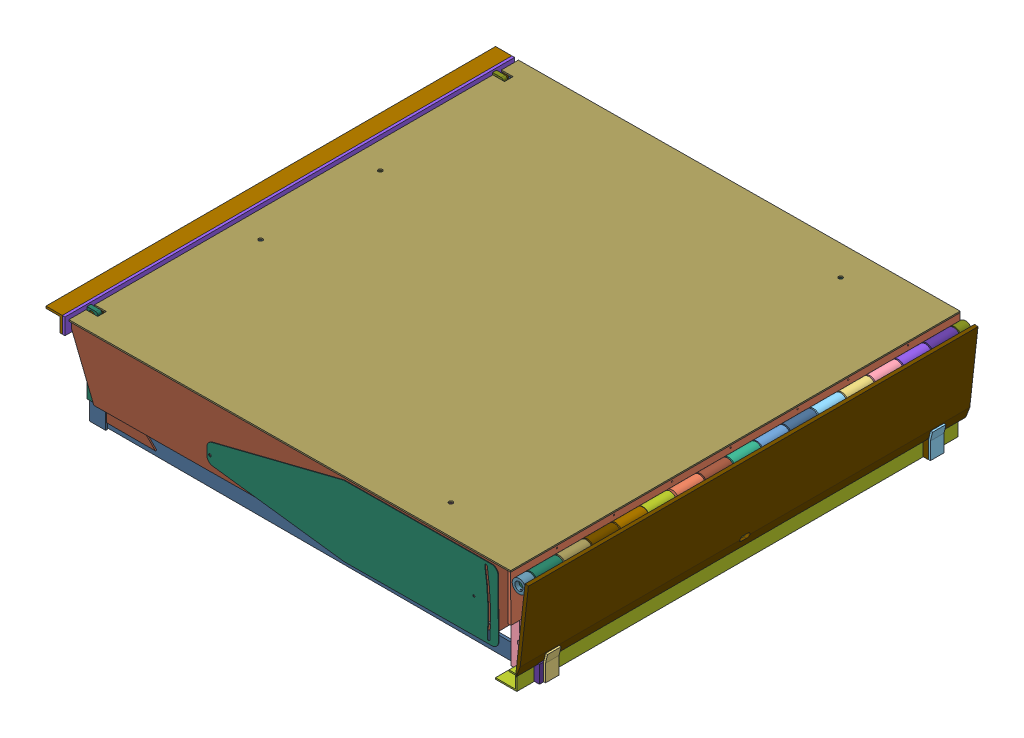
SolidWorks assembly MODELO NH 8X7 60K L16 especial, configuration Predeterminado. Lengths in mm.
Overall size (2261.63 523.31 2108).
138 component instances, 138 part files, 0 mates.
Components (placement in the parent):
- UH-1: UH [Predeterminado] at (-20837.1047 -5434.6461 -22380.9356) x (0 0 1) z (0 -1 0) size (202 682 216)
- MODELO NH 8X7 60K L16 especial2-1: MODELO NH 8X7 60K L16 especial2 [Predeterminado] at origin size (31.58 51.72 76.2)
- MODELO NH 8X7 60K L16 especial3-1: MODELO NH 8X7 60K L16 especial3 [Predeterminado] at origin size (31.58 51.72 76.2)
- MODELO NH 8X7 60K L16 especial4-1: MODELO NH 8X7 60K L16 especial4 [Predeterminado] at origin size (29.63 52.04 76.2)
- MODELO NH 8X7 60K L16 especial5-1: MODELO NH 8X7 60K L16 especial5 [Predeterminado] at origin size (31.58 51.72 76.2)
- MODELO NH 8X7 60K L16 especial6-1: MODELO NH 8X7 60K L16 especial6 [Predeterminado] at origin size (29.63 52.04 76.2)
- MODELO NH 8X7 60K L16 especial7-1: MODELO NH 8X7 60K L16 especial7 [Predeterminado] at origin size (31.58 51.72 76.2)
- MODELO NH 8X7 60K L16 especial8-1: MODELO NH 8X7 60K L16 especial8 [Predeterminado] at origin size (29.63 52.04 76.2)
- MODELO NH 8X7 60K L16 especial9-1: MODELO NH 8X7 60K L16 especial9 [Predeterminado] at origin size (31.58 51.72 76.2)
- MODELO NH 8X7 60K L16 especial10-1: MODELO NH 8X7 60K L16 especial10 [Predeterminado] at origin size (31.58 51.72 76.2)
- MODELO NH 8X7 60K L16 especial11-1: MODELO NH 8X7 60K L16 especial11 [Predeterminado] at origin size (31.58 51.72 76.2)
- MODELO NH 8X7 60K L16 especial12-1: MODELO NH 8X7 60K L16 especial12 [Predeterminado] at origin size (29.63 52.04 76.2)
- MODELO NH 8X7 60K L16 especial13-1: MODELO NH 8X7 60K L16 especial13 [Predeterminado] at origin size (31.58 51.72 76.2)
- MODELO NH 8X7 60K L16 especial14-1: MODELO NH 8X7 60K L16 especial14 [Predeterminado] at origin size (29.63 52.04 76.2)
- MODELO NH 8X7 60K L16 especial15-1: MODELO NH 8X7 60K L16 especial15 [Predeterminado] at origin size (52.14 40.87 51.7)
- MODELO NH 8X7 60K L16 especial16-1: MODELO NH 8X7 60K L16 especial16 [Predeterminado] at origin size (377.14 41.23 25.4)
- MODELO NH 8X7 60K L16 especial17-1: MODELO NH 8X7 60K L16 especial17 [Predeterminado] at origin size (43.03 51.76 50)
- MODELO NH 8X7 60K L16 especial18-1: MODELO NH 8X7 60K L16 especial18 [Predeterminado] at origin size (67.35 52.69 9.5)
- MODELO NH 8X7 60K L16 especial19-1: MODELO NH 8X7 60K L16 especial19 [Predeterminado] at origin size (67.35 52.69 9.5)
- MODELO NH 8X7 60K L16 especial20-1: MODELO NH 8X7 60K L16 especial20 [Predeterminado] at origin size (34.99 66.4 66)
- MODELO NH 8X7 60K L16 especial21-1: MODELO NH 8X7 60K L16 especial21 [Predeterminado] at origin size (270.47 75.91 63.5)
- MODELO NH 8X7 60K L16 especial22-1: MODELO NH 8X7 60K L16 especial22 [Predeterminado] at origin size (30.03 64.53 63.82)
- MODELO NH 8X7 60K L16 especial23-1: MODELO NH 8X7 60K L16 especial23 [Predeterminado] at origin size (92.65 87.43 65.1)
- MODELO NH 8X7 60K L16 especial24-1: MODELO NH 8X7 60K L16 especial24 [Predeterminado] at origin size (575.9 347.01 63.5)
- MODELO NH 8X7 60K L16 especial25-1: MODELO NH 8X7 60K L16 especial25 [Predeterminado] at origin size (612.93 343.69 39.94)
- MODELO NH 8X7 60K L16 especial26-1: MODELO NH 8X7 60K L16 especial26 [Predeterminado] at origin size (55.77 66.38 66)
- MODELO NH 8X7 60K L16 especial27-1: MODELO NH 8X7 60K L16 especial27 [Predeterminado] at origin size (57.33 62.14 50)
- MODELO NH 8X7 60K L16 especial28-1: MODELO NH 8X7 60K L16 especial28 [Predeterminado] at origin size (2082.47 76.2 76.2)
- MODELO NH 8X7 60K L16 especial29-1: MODELO NH 8X7 60K L16 especial29 [Predeterminado] at origin size (2061.6 313.69 2.66)
- MODELO NH 8X7 60K L16 especial30-1: MODELO NH 8X7 60K L16 especial30 [Predeterminado] at origin size (2071.04 22.48 2108)
- MODELO NH 8X7 60K L16 especial31-1: MODELO NH 8X7 60K L16 especial31 [Predeterminado] at origin size (51.86 102.13 19)
- MODELO NH 8X7 60K L16 especial32-1: MODELO NH 8X7 60K L16 especial32 [Predeterminado] at origin size (51.86 102.13 19)
- MODELO NH 8X7 60K L16 especial33-1: MODELO NH 8X7 60K L16 especial33 [Predeterminado] at origin size (19.44 50.15 271.82)
- MODELO NH 8X7 60K L16 especial34-1: MODELO NH 8X7 60K L16 especial34 [Predeterminado] at origin size (1062.97 52.9 50.8)
- MODELO NH 8X7 60K L16 especial35-1: MODELO NH 8X7 60K L16 especial35 [Predeterminado] at origin size (33.39 244.2 2057.2)
- MODELO NH 8X7 60K L16 especial36-1: MODELO NH 8X7 60K L16 especial36 [Predeterminado] at origin size (59.99 397.88 2108)
- MODELO NH 8X7 60K L16 especial37-1: MODELO NH 8X7 60K L16 especial37 [Predeterminado] at origin size (142.05 166.76 2062.76)
- MODELO NH 8X7 60K L16 especial38-1: MODELO NH 8X7 60K L16 especial38 [Predeterminado] at origin size (14.37 215.1 2108)
- MODELO NH 8X7 60K L16 especial39-1: MODELO NH 8X7 60K L16 especial39 [Predeterminado] at origin size (1952.22 175.19 98)
- MODELO NH 8X7 60K L16 especial40-1: MODELO NH 8X7 60K L16 especial40 [Predeterminado] at origin size (1952.22 175.19 98)
- MODELO NH 8X7 60K L16 especial41-1: MODELO NH 8X7 60K L16 especial41 [Predeterminado] at origin size (1952.22 175.19 98)
- MODELO NH 8X7 60K L16 especial42-1: MODELO NH 8X7 60K L16 especial42 [Predeterminado] at origin size (1952.22 175.19 98)
- MODELO NH 8X7 60K L16 especial43-1: MODELO NH 8X7 60K L16 especial43 [Predeterminado] at origin size (1952.22 175.19 98)
- MODELO NH 8X7 60K L16 especial44-1: MODELO NH 8X7 60K L16 especial44 [Predeterminado] at origin size (1952.22 175.19 98)
- MODELO NH 8X7 60K L16 especial45-1: MODELO NH 8X7 60K L16 especial45 [Predeterminado] at origin size (1952.22 175.19 98)
- MODELO NH 8X7 60K L16 especial46-1: MODELO NH 8X7 60K L16 especial46 [Predeterminado] at origin size (1952.22 175.19 98)
- MODELO NH 8X7 60K L16 especial47-1: MODELO NH 8X7 60K L16 especial47 [Predeterminado] at origin size (10.49 63.58 63.5)
- MODELO NH 8X7 60K L16 especial48-1: MODELO NH 8X7 60K L16 especial48 [Predeterminado] at origin size (10.49 63.58 63.5)
- MODELO NH 8X7 60K L16 especial49-1: MODELO NH 8X7 60K L16 especial49 [Predeterminado] at origin size (2061.6 313.69 2.66)
- MODELO NH 8X7 60K L16 especial50-1: MODELO NH 8X7 60K L16 especial50 [Predeterminado] at origin size (63.5 63.5 50)
- MODELO NH 8X7 60K L16 especial51-1: MODELO NH 8X7 60K L16 especial51 [Predeterminado] at origin size (63.5 63.5 127)
- MODELO NH 8X7 60K L16 especial52-1: MODELO NH 8X7 60K L16 especial52 [Predeterminado] at origin size (63.5 63.5 50)
- MODELO NH 8X7 60K L16 especial53-1: MODELO NH 8X7 60K L16 especial53 [Predeterminado] at origin size (63.5 63.5 127)
- MODELO NH 8X7 60K L16 especial54-1: MODELO NH 8X7 60K L16 especial54 [Predeterminado] at origin size (31.75 31.75 2069.2)
- MODELO NH 8X7 60K L16 especial55-1: MODELO NH 8X7 60K L16 especial55 [Predeterminado] at origin size (10.12 76.27 2071.67)
- MODELO NH 8X7 60K L16 especial56-1: MODELO NH 8X7 60K L16 especial56 [Predeterminado] at origin size (51.64 108.34 190.5)
- MODELO NH 8X7 60K L16 especial57-1: MODELO NH 8X7 60K L16 especial57 [Predeterminado] at origin size (51.64 108.34 190.5)
- MODELO NH 8X7 60K L16 especial58-1: MODELO NH 8X7 60K L16 especial58 [Predeterminado] at origin size (76.2 76.2 1859.26)
- MODELO NH 8X7 60K L16 especial59-1: MODELO NH 8X7 60K L16 especial59 [Predeterminado] at origin size (63.25 59.43 19.05)
- MODELO NH 8X7 60K L16 especial60-1: MODELO NH 8X7 60K L16 especial60 [Predeterminado] at origin size (63.25 59.43 19.05)
- MODELO NH 8X7 60K L16 especial61-1: MODELO NH 8X7 60K L16 especial61 [Predeterminado] at origin size (100.01 70 2068.06)
- MODELO NH 8X7 60K L16 especial62-1: MODELO NH 8X7 60K L16 especial62 [Predeterminado] at origin size (12.7 76.2 2108)
- MODELO NH 8X7 60K L16 especial63-1: MODELO NH 8X7 60K L16 especial63 [Predeterminado] at origin size (76.2 76.2 2108)
- MODELO NH 8X7 60K L16 especial64-1: MODELO NH 8X7 60K L16 especial64 [Predeterminado] at origin size (25.4 25.4 847.56)
- MODELO NH 8X7 60K L16 especial65-1: MODELO NH 8X7 60K L16 especial65 [Predeterminado] at origin size (2082.47 76.2 76.2)
- MODELO NH 8X7 60K L16 especial66-1: MODELO NH 8X7 60K L16 especial66 [Predeterminado] at origin size (76.2 417 76.2)
- MODELO NH 8X7 60K L16 especial67-1: MODELO NH 8X7 60K L16 especial67 [Predeterminado] at origin size (63.5 200 28.26)
- MODELO NH 8X7 60K L16 especial68-1: MODELO NH 8X7 60K L16 especial68 [Predeterminado] at origin size (19.55 25.17 28.93)
- MODELO NH 8X7 60K L16 especial69-1: MODELO NH 8X7 60K L16 especial69 [Predeterminado] at origin size (34.92 34.92 2058)
- MODELO NH 8X7 60K L16 especial70-1: MODELO NH 8X7 60K L16 especial70 [Predeterminado] at origin size (63.25 59.43 19.05)
- MODELO NH 8X7 60K L16 especial71-1: MODELO NH 8X7 60K L16 especial71 [Predeterminado] at origin size (63.25 59.43 19.05)
- MODELO NH 8X7 60K L16 especial72-1: MODELO NH 8X7 60K L16 especial72 [Predeterminado] at origin size (63.25 59.43 19.05)
- MODELO NH 8X7 60K L16 especial73-1: MODELO NH 8X7 60K L16 especial73 [Predeterminado] at origin size (63.25 59.43 19.05)
- MODELO NH 8X7 60K L16 especial74-1: MODELO NH 8X7 60K L16 especial74 [Predeterminado] at origin size (63.25 59.43 19.05)
- MODELO NH 8X7 60K L16 especial75-1: MODELO NH 8X7 60K L16 especial75 [Predeterminado] at origin size (21.07 25.05 28.93)
- MODELO NH 8X7 60K L16 especial76-1: MODELO NH 8X7 60K L16 especial76 [Predeterminado] at origin size (25.17 21.07 28.93)
- MODELO NH 8X7 60K L16 especial77-1: MODELO NH 8X7 60K L16 especial77 [Predeterminado] at origin size (25.17 21.07 28.93)
- MODELO NH 8X7 60K L16 especial78-1: MODELO NH 8X7 60K L16 especial78 [Predeterminado] at origin size (25.17 21.07 28.93)
- MODELO NH 8X7 60K L16 especial79-1: MODELO NH 8X7 60K L16 especial79 [Predeterminado] at origin size (25.17 21.07 28.93)
- MODELO NH 8X7 60K L16 especial80-1: MODELO NH 8X7 60K L16 especial80 [Predeterminado] at origin size (86.72 55.18 19.05)
- MODELO NH 8X7 60K L16 especial81-1: MODELO NH 8X7 60K L16 especial81 [Predeterminado] at origin size (53.88 53.88 3.18)
- MODELO NH 8X7 60K L16 especial82-1: MODELO NH 8X7 60K L16 especial82 [Predeterminado] at origin size (83.2 82.19 15.88)
- MODELO NH 8X7 60K L16 especial83-1: MODELO NH 8X7 60K L16 especial83 [Predeterminado] at origin size (68.45 67.53 15.87)
- MODELO NH 8X7 60K L16 especial84-1: MODELO NH 8X7 60K L16 especial84 [Predeterminado] at origin size (53.88 53.88 3.18)
- MODELO NH 8X7 60K L16 especial85-1: MODELO NH 8X7 60K L16 especial85 [Predeterminado] at origin size (83.2 82.19 15.88)
- MODELO NH 8X7 60K L16 especial86-1: MODELO NH 8X7 60K L16 especial86 [Predeterminado] at origin size (68.45 67.53 15.87)
- MODELO NH 8X7 60K L16 especial87-1: MODELO NH 8X7 60K L16 especial87 [Predeterminado] at origin size (1366.94 335.39 2.66)
- MODELO NH 8X7 60K L16 especial88-1: MODELO NH 8X7 60K L16 especial88 [Predeterminado] at origin size (1366.94 335.39 2.66)
- MODELO NH 8X7 60K L16 especial89-1: MODELO NH 8X7 60K L16 especial89 [Predeterminado] at origin size (25.4 81 63.5)
- MODELO NH 8X7 60K L16 especial90-1: MODELO NH 8X7 60K L16 especial90 [Predeterminado] at origin size (25.4 81 63.5)
- MODELO NH 8X7 60K L16 especial91-1: MODELO NH 8X7 60K L16 especial91 [Predeterminado] at origin size (101.65 7.14 246.2)
- MODELO NH 8X7 60K L16 especial92-1: MODELO NH 8X7 60K L16 especial92 [Predeterminado] at origin size (101.65 7.14 246.2)
- MODELO NH 8X7 60K L16 especial93-1: MODELO NH 8X7 60K L16 especial93 [Predeterminado] at origin size (19.05 120 63.5)
- MODELO NH 8X7 60K L16 especial94-1: MODELO NH 8X7 60K L16 especial94 [Predeterminado] at origin size (114.31 236.38 19.08)
- MODELO NH 8X7 60K L16 especial95-1: MODELO NH 8X7 60K L16 especial95 [Predeterminado] at origin size (19.05 120 63.5)
- MODELO NH 8X7 60K L16 especial96-1: MODELO NH 8X7 60K L16 especial96 [Predeterminado] at origin size (114.31 236.38 19.08)
- MODELO NH 8X7 60K L16 especial97-1: MODELO NH 8X7 60K L16 especial97 [Predeterminado] at origin size (9.53 81 63.5)
- MODELO NH 8X7 60K L16 especial98-1: MODELO NH 8X7 60K L16 especial98 [Predeterminado] at origin size (76.2 50.8 19.05)
- MODELO NH 8X7 60K L16 especial99-1: MODELO NH 8X7 60K L16 especial99 [Predeterminado] at origin size (76.2 50.8 19.05)
- MODELO NH 8X7 60K L16 especial100-1: MODELO NH 8X7 60K L16 especial100 [Predeterminado] at origin size (76.2 418.8 76.2)
- MODELO NH 8X7 60K L16 especial101-1: MODELO NH 8X7 60K L16 especial101 [Predeterminado] at origin size (76.2 418.8 76.2)
- MODELO NH 8X7 60K L16 especial102-1: MODELO NH 8X7 60K L16 especial102 [Predeterminado] at origin size (63.25 59.43 19.05)
- MODELO NH 8X7 60K L16 especial103-1: MODELO NH 8X7 60K L16 especial103 [Predeterminado] at origin size (63.5 200 28.26)
- MODELO NH 8X7 60K L16 especial104-1: MODELO NH 8X7 60K L16 especial104 [Predeterminado] at origin size (64.76 63.5 53.97)
- MODELO NH 8X7 60K L16 especial105-1: MODELO NH 8X7 60K L16 especial105 [Predeterminado] at origin size (63.25 59.43 19.05)
- MODELO NH 8X7 60K L16 especial106-1: MODELO NH 8X7 60K L16 especial106 [Predeterminado] at origin size (63.25 59.43 19.05)
- MODELO NH 8X7 60K L16 especial107-1: MODELO NH 8X7 60K L16 especial107 [Predeterminado] at origin size (63.25 59.43 19.05)
- MODELO NH 8X7 60K L16 especial108-1: MODELO NH 8X7 60K L16 especial108 [Predeterminado] at origin size (63.25 59.43 19.05)
- MODELO NH 8X7 60K L16 especial109-1: MODELO NH 8X7 60K L16 especial109 [Predeterminado] at origin size (25.4 25.4 260)
- MODELO NH 8X7 60K L16 especial110-1: MODELO NH 8X7 60K L16 especial110 [Predeterminado] at origin size (152.4 10.07 177.8)
- MODELO NH 8X7 60K L16 especial111-1: MODELO NH 8X7 60K L16 especial111 [Predeterminado] at origin size (532.77 36.49 25.4)
- MODELO NH 8X7 60K L16 especial112-1: MODELO NH 8X7 60K L16 especial112 [Predeterminado] at origin size (134.17 198.1 38.1)
- MODELO NH 8X7 60K L16 especial113-1: MODELO NH 8X7 60K L16 especial113 [Predeterminado] at origin size (9.53 9.53 63.5)
- MODELO NH 8X7 60K L16 especial114-1: MODELO NH 8X7 60K L16 especial114 [Predeterminado] at origin size (675.43 52.15 38.1)
- MODELO NH 8X7 60K L16 especial115-1: MODELO NH 8X7 60K L16 especial115 [Predeterminado] at origin size (25.4 22 12.7)
- MODELO NH 8X7 60K L16 especial116-1: MODELO NH 8X7 60K L16 especial116 [Predeterminado] at origin size (16.12 16.17 89.72)
- MODELO NH 8X7 60K L16 especial117-1: MODELO NH 8X7 60K L16 especial117 [Predeterminado] at origin size (1066.8 9.53 165.1)
- MODELO NH 8X7 60K L16 especial118-1: MODELO NH 8X7 60K L16 especial118 [Predeterminado] at origin size (230 230 6.35)
- MODELO NH 8X7 60K L16 especial119-1: MODELO NH 8X7 60K L16 especial119 [Predeterminado] at origin size (230 230 6.35)
- MODELO NH 8X7 60K L16 especial120-1: MODELO NH 8X7 60K L16 especial120 [Predeterminado] at origin size (50.93 120.39 19.05)
- MODELO NH 8X7 60K L16 especial121-1: MODELO NH 8X7 60K L16 especial121 [Predeterminado] at origin size (101.65 7.14 184)
- MODELO NH 8X7 60K L16 especial122-1: MODELO NH 8X7 60K L16 especial122 [Predeterminado] at origin size (10.49 63.58 63.5)
- MODELO NH 8X7 60K L16 especial123-1: MODELO NH 8X7 60K L16 especial123 [Predeterminado] at origin size (50.8 374.69 19.05)
- MODELO NH 8X7 60K L16 especial124-1: MODELO NH 8X7 60K L16 especial124 [Predeterminado] at origin size (50.8 374.69 19.05)
- MODELO NH 8X7 60K L16 especial125-1: MODELO NH 8X7 60K L16 especial125 [Predeterminado] at origin size (29.63 52.04 76.2)
- MODELO NH 8X7 60K L16 especial126-1: MODELO NH 8X7 60K L16 especial126 [Predeterminado] at origin size (63.5 63.5 126.99)
- MODELO NH 8X7 60K L16 especial127-1: MODELO NH 8X7 60K L16 especial127 [Predeterminado] at origin size (63.5 63.5 127)
- MODELO NH 8X7 60K L16 especial128-1: MODELO NH 8X7 60K L16 especial128 [Predeterminado] at origin size (63.5 63.5 127)
- MODELO NH 8X7 60K L16 especial129-1: MODELO NH 8X7 60K L16 especial129 [Predeterminado] at origin size (63.5 63.5 127)
- MODELO NH 8X7 60K L16 especial130-1: MODELO NH 8X7 60K L16 especial130 [Predeterminado] at origin size (63.5 63.5 127)
- MODELO NH 8X7 60K L16 especial131-1: MODELO NH 8X7 60K L16 especial131 [Predeterminado] at origin size (63.5 63.5 127)
- MODELO NH 8X7 60K L16 especial132-1: MODELO NH 8X7 60K L16 especial132 [Predeterminado] at origin size (63.5 63.5 127)
- MODELO NH 8X7 60K L16 especial133-1: MODELO NH 8X7 60K L16 especial133 [Predeterminado] at origin size (63.5 63.5 127)
- MODELO NH 8X7 60K L16 especial134-1: MODELO NH 8X7 60K L16 especial134 [Predeterminado] at origin size (63.5 63.5 127)
- MODELO NH 8X7 60K L16 especial135-1: MODELO NH 8X7 60K L16 especial135 [Predeterminado] at origin size (63.5 63.5 127)
- MODELO NH 8X7 60K L16 especial136-1: MODELO NH 8X7 60K L16 especial136 [Predeterminado] at origin size (63.5 63.5 127)
- MODELO NH 8X7 60K L16 especial137-1: MODELO NH 8X7 60K L16 especial137 [Predeterminado] at origin size (63.5 63.5 127)
- MODELO NH 8X7 60K L16 especial138-1: MODELO NH 8X7 60K L16 especial138 [Predeterminado] at origin size (63.5 63.5 127)
